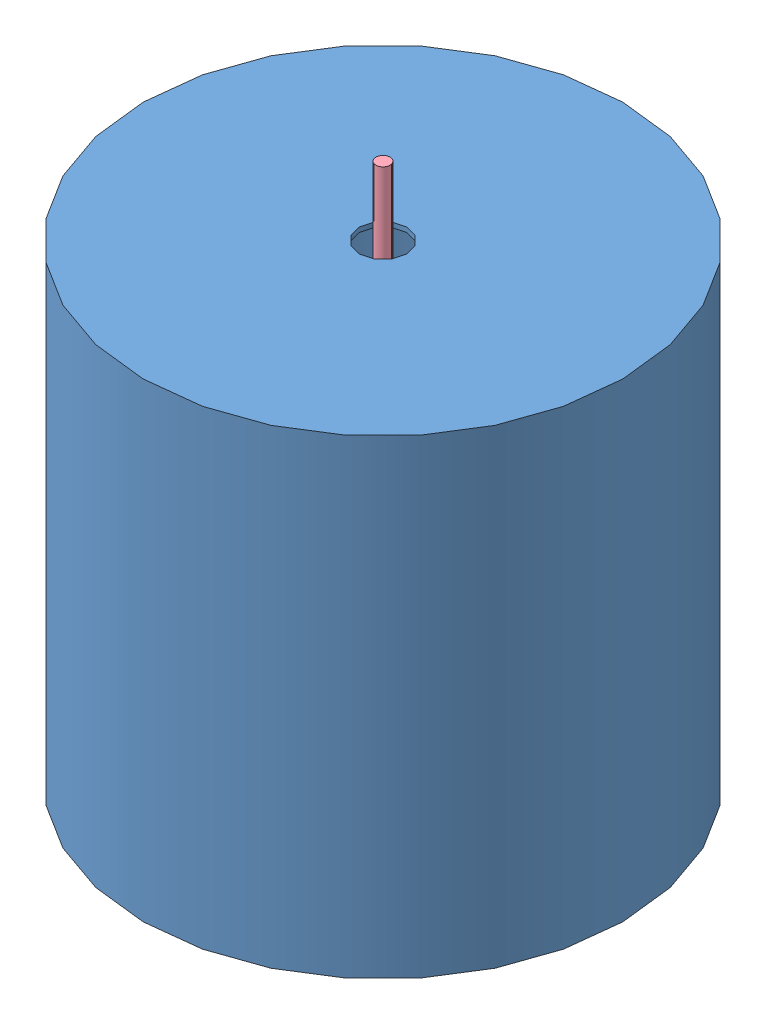
SolidWorks assembly Diyafram, configuration Default. Lengths in mm.
Overall size (102 126 102).
4 component instances, 4 part files, 6 mates.
Components (placement in the parent):
- Hazne-1: Hazne [Default] at origin size (102 100 102)
- balon-1: balon [Default] at (0 -0.5 0) x (0.976762 0 -0.214327) z (0.214327 0 0.976762) size (30 0.5 30)
- Kure-1: Kure [Default] at (0 -5.3734 0) x (0.979251 0 -0.20265) z (0.20265 0 0.979251) size (12 11.81 12)
- mil-1: mil [Default] at (0 -5.3734 0) x (0.050974 0 -0.9987) z (0.9987 0 0.050974) size (3 120 3)
Mates (geometry in assembly coordinates):
- Coincident1: coincident anti-aligned: plane of Kure-1 through (0 -5.3734 0) normal (0 1 0); plane of mil-1 through (0 -5.3734 0) normal (0 -1 0)
- Concentric1: concentric aligned: cylinder of Kure-1 through (0 0.6266 0) axis (0 -1 0) radius 1.5; cylinder of mil-1 through (0 114.6266 0) axis (0 -1 0) radius 1.5
- Concentric2: concentric aligned: cylinder of Hazne-1 through (0 100 0) axis (0 -1 0) radius 5; cylinder of balon-1 through (0 0 0) axis (0 -1 0) radius 3.5
- Coincident2: coincident anti-aligned: plane of Hazne-1 through (0 0 0) normal (0 -1 0); plane of balon-1 through (0 0 0) normal (0 1 0)
- Concentric3: concentric aligned: cylinder of Hazne-1 through (0 100 0) axis (0 -1 0) radius 5; cylinder of mil-1 through (0 114.6266 0) axis (0 -1 0) radius 1.5
- Tangent1: tangent: circle of balon-1; sphere of Kure-1
